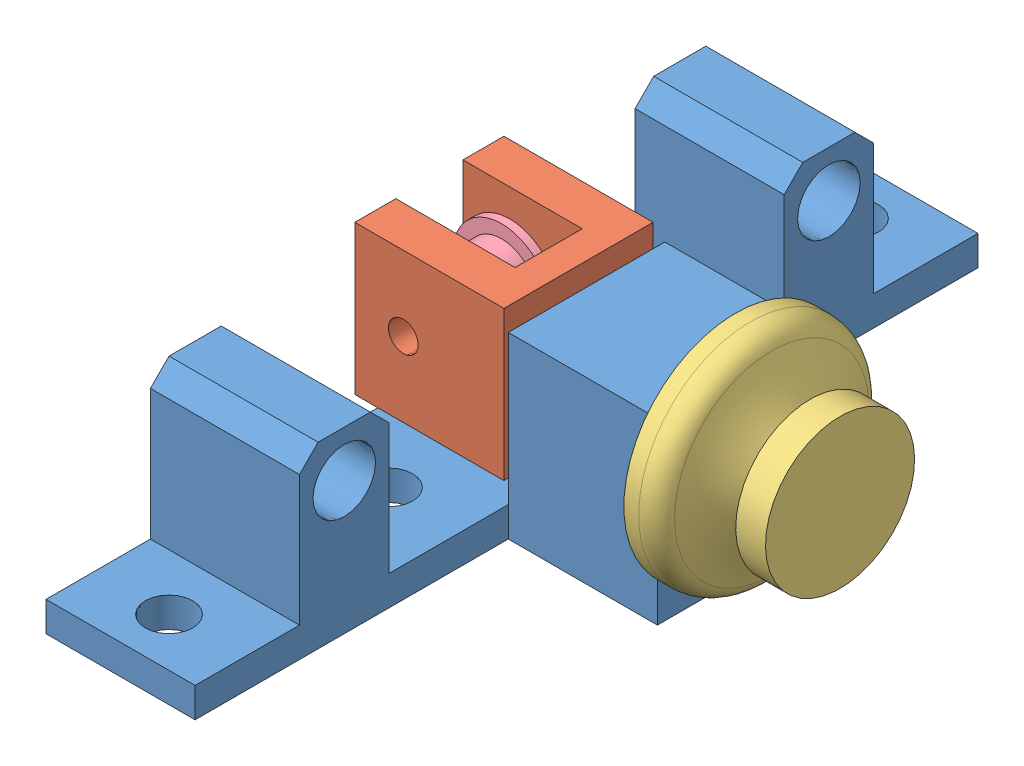
SolidWorks assembly Assem2, configuration Default. Lengths in mm.
Overall size (62.66 40.38 105).
4 component instances, 4 part files, 6 mates.
Components (placement in the parent):
- longRodMount-1: longRodMount [Default] at (10.6819 34.0554 109.7318) size (48.66 24 105)
- 10mmAntiScrew-1: 10mmAntiScrew [Default] at (29.5993 50.0554 57.2318) x (0 0 1) z (0 1 0) size (20 40 20)
- screw-1: screw [Default] at (30.6819 50.0554 57.2318) x (0 0.889951 -0.456056) z (0 -0.456056 -0.889951) size (30 35.38 30)
- 3mmSprocket-1: 3mmSprocket [Default] at (16.0993 50.0554 61.5168) x (0.812796 0.582548 0) z (-0.582548 0.812796 0) size (13 8.57 13)
Mates (geometry in assembly coordinates):
- Concentric1: concentric anti-aligned: cylinder of longRodMount-1 through (2.0217 50.0554 57.2318) axis (1 0 0) radius 6; cylinder of 10mmAntiScrew-1 through (49.5993 50.0554 57.2318) axis (-1 0 0) radius 6
- Parallel1: parallel anti-aligned: plane of longRodMount-1 through (54.0057 34.0554 95.7318) normal (0 0 1); plane of 10mmAntiScrew-1 through (25.5993 60.0554 47.2318) normal (0 0 -1)
- Concentric2: concentric anti-aligned: circle of 10mmAntiScrew-1; cylinder of screw-1 through (64.6819 50.0554 57.2318) axis (-1 0 0) radius 10
- Coincident2: coincident anti-aligned: plane of longRodMount-1 through (50.6819 34.0554 109.7318) normal (1 0 0); plane of screw-1 through (50.6819 50.0554 57.2318) normal (-1 0 0)
- Concentric3: concentric anti-aligned: cylinder of 10mmAntiScrew-1 through (16.0993 50.0554 47.2318) axis (0 0 1) radius 2; cylinder of 3mmSprocket-1 through (16.0993 50.0554 61.5168) axis (0 0 -1) radius 1.5
- Width1: width anti-aligned: plane of 3mmSprocket-1 through (16.0993 50.0554 52.9468) normal (0 0 -1); plane of 10mmAntiScrew-1 through (16.0993 50.0554 61.5168) normal (0 0 1); plane of 3mmSprocket-1 through (29.5993 19.3129 52.7318) normal (0 0 1); plane of 10mmAntiScrew-1 through (29.5993 19.3129 61.7318) normal (0 0 -1)
